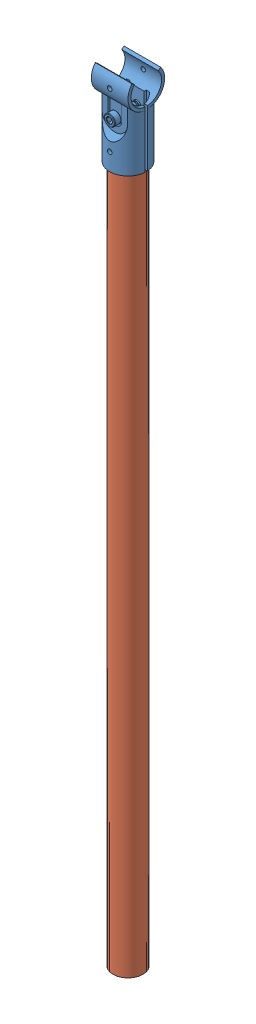
SolidWorks assembly 1120-Post, configuration Default. Lengths in mm.
Overall size (33.53 713.41 34.1).
2 component instances, 2 part files, 2 mates.
Components (placement in the parent):
- 6015-ClampOpen-1: 6015-ClampOpen [2534T22] at (63.1228 720.8951 -239.7753) size (33.53 76.2 34.1)
- 6010-PipeSide-3: 6010-PipeSide [2534T132] at (63.1228 348.0978 -239.7753) x (1 0 0) z (0 1 0) size (27.43 27.43 660.4)
Mates (geometry in assembly coordinates):
- Concentric9: concentric: circle of 6015-ClampOpen-1; cylinder of 6010-PipeSide-3 through (63.1228 678.2978 -239.7753) axis (0 -1 0) radius 13.716
- Lock1: lock: unknown of 6015-ClampOpen-1; unknown of 6010-PipeSide-3
